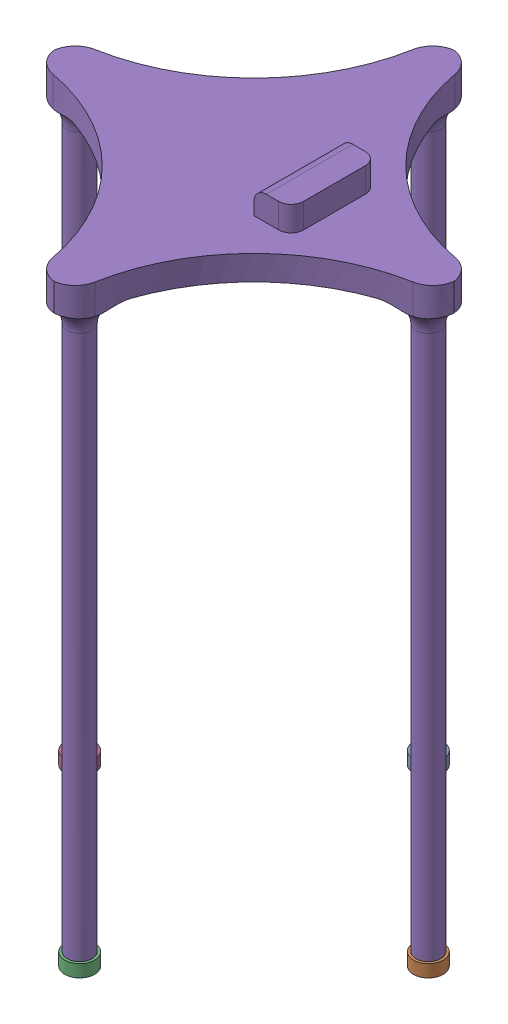
SolidWorks assembly Transmision - Ensamblaje, configuration Predeterminado. Lengths in mm.
Overall size (162 255 162).
6 component instances, 5 part files, 5 mates.
Components (placement in the parent):
- Transmision - T1-1: Transmision - T1 [Predeterminado] at (13.6304 93.7099 80.9197) size (162 255 162)
- Eje de Conexion - T2-1: Eje de Conexion - T2 [Predeterminado] at (13.6304 73.7099 80.9197) size (5 20 5)
- Fin de carrera-1: Fin de carrera [Default] at (18.4866 113.618 76.5372) x (0 0 1) z (1 0 0) size (20.3 23.07 6.6)
  - Limit switch-1: Limit switch [Default] at (-5.6175 18.1081 17.0438) size (20 15.2 6.6)
  - steel-1: steel [Default] at (13.5838 19.3646 18.3438) x (-0.985639 0.168868 0) z (0 0 1) size (19 9.3 6.6)
  - roller-1: roller [Default] at (-2.8697 25.4809 18.3438) x (0 0 1) z (-1 0 0) size (4 5 5)
Mates (geometry in assembly coordinates):
- Concéntrica1: concentric anti-aligned: cylinder of Transmision - T1-1 through (13.6304 83.7099 80.9197) axis (0 1 0) radius 2.5; cylinder of Eje de Conexion-1 through (13.6304 93.7099 80.9197) axis (0 -1 0) radius 2.5
- Concéntrica6: concentric anti-aligned: cylinder of Transmision - T1-1 through (13.6304 88.2099 161.9207) axis (0 0 -1) radius 0.75; cylinder of Eje de Conexion-1 through (13.6304 88.2099 78.4187) axis (0 0 1) radius 0.75
- Coincidente3: coincident anti-aligned: plane of Transmision - T1-1 through (42.1304 108.7099 90.9197) normal (-1 0 0); plane of Fin de carrera-1/Limit switch-1 through (42.1304 95.5099 70.9197) normal (1 0 0)
- Coincidente4: coincident anti-aligned: plane of Transmision - T1-1 through (35.1304 108.7099 90.9197) normal (0 0 -1); plane of Fin de carrera-1/Limit switch-1 through (42.1304 95.5099 90.9197) normal (0 0 1)
- Coincidente5: coincident anti-aligned: plane of Transmision - T1-1 through (13.6304 108.7099 80.9197) normal (0 -1 0); plane of Assem1-1/Limit switch-1 through (35.5304 108.7099 70.9197) normal (0 1 0)
